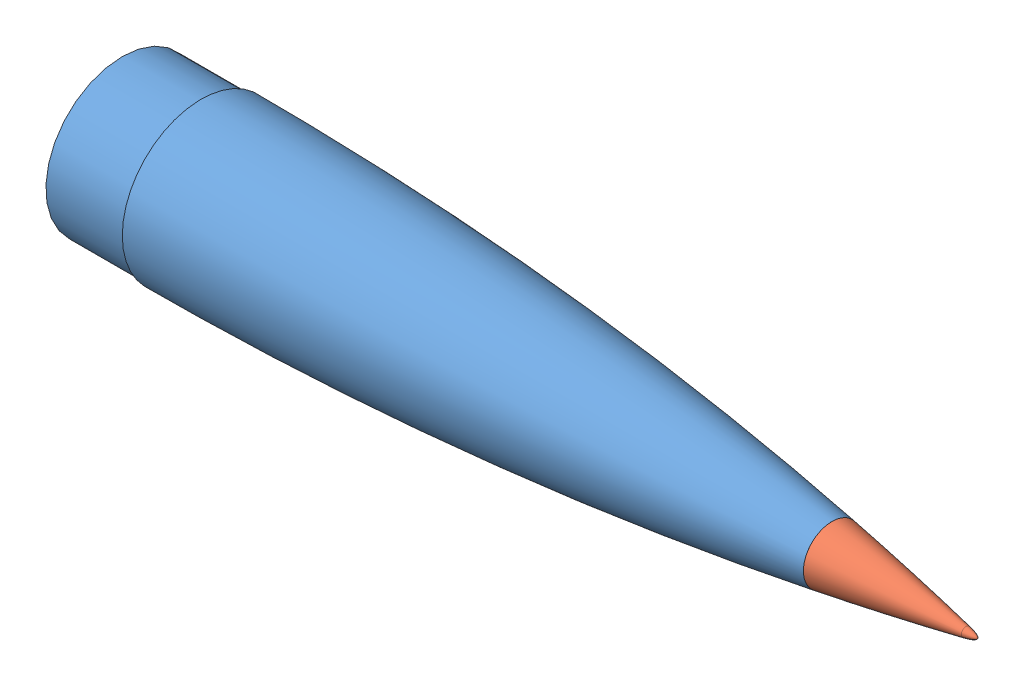
SolidWorks assembly COTS Tangent Ogive Nose Cone with metal tip - 8 inch, configuration Default. Lengths in mm.
Overall size (1101.93 203.2 203.2).
2 component instances, 2 part files, 5 mates.
Components (placement in the parent):
- Tangent_Ogive_Nosecone_01-1: Tangent_Ogive_Nosecone_01 [40in] x (0 0 -1) z (0 -1 0) size (203.2 914.4 203.2)
- Tangent_Ogive_Nosecone_02-1: Tangent_Ogive_Nosecone_02 [40in] x (0 0 -1) z (0 -1 0) size (73.62 187.53 73.62)
Mates (geometry in assembly coordinates):
- Coincident1: coincident aligned: plane of Tangent_Ogive_Nosecone_01-1 through (0 0 0) normal (1 0 0)
- Coincident2: coincident anti-aligned: plane of Tangent_Ogive_Nosecone_01-1 through (0 0 0) normal (0 -1 0)
- Coincident3: coincident anti-aligned: plane of Tangent_Ogive_Nosecone_02-1 through (0 0 0) normal (0 -1 0)
- Coincident4: coincident aligned: plane of Tangent_Ogive_Nosecone_02-1 through (0 0 0) normal (1 0 0)
- Coincident5: coincident anti-aligned: plane of Tangent_Ogive_Nosecone_02-1 through (0 0 0) normal (0 0 -1)
